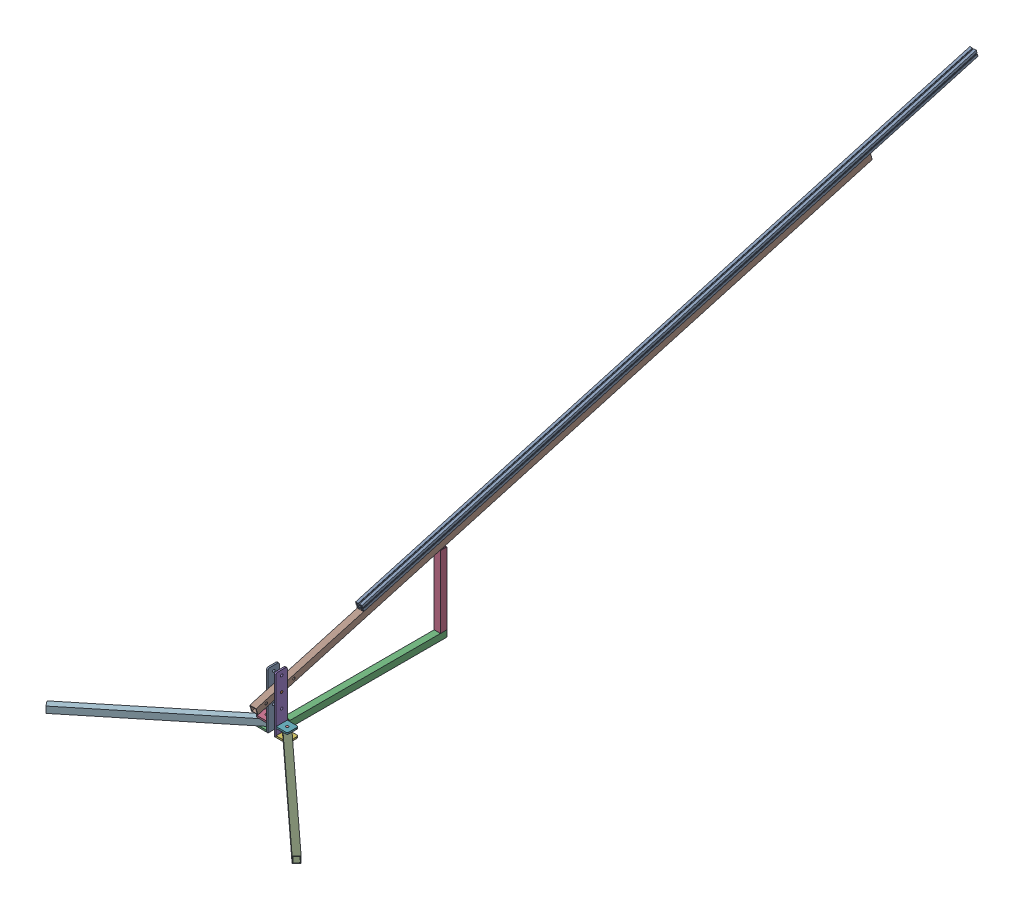
SolidWorks assembly plataformaDeLansamiento, configuration Predeterminado. Lengths in mm.
Overall size (1637.54 1526.39 5050.55).
16 component instances, 8 part files, 39 mates.
Components (placement in the parent):
- soporteEsctructura-1: soporteEsctructura [Predeterminado] at (70.7592 -29.7484 26.1138) x (0 0 -1) z (0 -1 0) size (70 10 350)
- union-1: union [Predeterminado] at (130.7592 25.2516 26.1138) x (0 -0.796552 0.604571) z (0 -0.604571 -0.796552) size (15 60 15)
- soporteLateral-1: soporteLateral [Predeterminado] at (35.7592 -194.7484 26.1138) x (0 0 -1) z (-1 0 0) size (70 10 70)
- soporteLateral-2: soporteLateral [Predeterminado] at (35.7592 -154.7484 26.1138) x (0 0 1) z (-1 0 0) size (70 10 70)
- soporteEsctructura-3: soporteEsctructura [Predeterminado] at (120.7592 -29.7484 26.1138) x (0 0 -1) z (0 -1 0) size (70 10 350)
- soporteLateral-3: soporteLateral [Predeterminado] at (165.7592 -204.7484 26.1138) x (0 0 -1) z (1 0 0) size (70 10 70)
- soporteLateral-4: soporteLateral [Predeterminado] at (165.7592 -154.7484 26.1138) x (0 0 -1) z (1 0 0) size (70 10 70)
- metalCuadrado-2: metalCuadrado [Predeterminado] at (100.7592 1073.3418 -3678.4789) x (1 0 0) z (0 -0.272231 0.962232) size (40 40 4000)
- soportePiso-1: soportePiso [Predeterminado] at (151.033 -174.7484 12.581) x (-0.676642 0 0.736312) z (0 1 0) size (40 1000 40)
- union-2: union [Predeterminado] at (165.7592 -204.7484 26.1138) size (15 60 15)
- union-3: union [Predeterminado] at (35.7592 -204.7484 26.1138) size (15 60 15)
- soportePiso-3: soportePiso [Predeterminado] at (51.2651 -174.7484 13.4818) x (0.631599 0 0.775295) z (0 -1 0) size (40 1000 40)
- aluminiumStructural-2: aluminiumStructural [Predeterminado] at (100.7592 1302.393 -4341.1519) x (1 0 0) z (0 -0.272231 0.962232) size (40 40 4000)
- soldarPieza-1: soldarPieza [Predeterminado] at (100.7592 -174.7484 -18.8862) size (60 60 10)
- soportePiso-4: soportePiso [Predeterminado] at (100.7592 -184.7484 -1018.8862) x (1 0 0) z (0 -1 0) size (40 1000 40)
- soporteSecundario-1: soporteSecundario [Predeterminado] at (100.7592 -164.7484 -998.8862) x (1 0 0) z (0 1 0) size (40 40 450)
Mates (geometry in assembly coordinates):
- Concéntrica2: concentric aligned: circle of soporteEsctructura-1; cylinder of union-1 through (70.7592 24.3437 26.1138) axis (1 0 0) radius 7.5
- Coincidente2: coincident aligned: plane of soporteEsctructura-1 through (70.7592 135.2516 51.1138) normal (-1 0 0); plane of union-1 through (70.7592 24.3437 26.1138) normal (-1 0 0)
- Coincidente3: coincident anti-aligned: plane of soporteEsctructura-1 through (70.7592 135.2516 51.1138) normal (-1 0 0); plane of soporteLateral-1 through (70.7592 -203.8405 61.1138) normal (1 0 0)
- Coincidente4: coincident aligned: plane of soporteEsctructura-1 through (80.7592 -204.7484 61.1138) normal (0 0 1); plane of soporteLateral-1 through (70.7592 -203.8405 61.1138) normal (0 0 1)
- Coincidente5: coincident aligned: plane of soporteEsctructura-1 through (80.7592 -204.7484 61.1138) normal (0 -1 0); plane of soporteLateral-1 through (10.7592 -203.8405 51.1138) normal (0 -1 0)
- Coincidente6: coincident anti-aligned: plane of soporteEsctructura-1 through (70.7592 135.2516 51.1138) normal (-1 0 0); plane of soporteLateral-2 through (70.7592 -143.8405 -8.8862) normal (1 0 0)
- Coincidente7: coincident aligned: plane of soporteEsctructura-1 through (80.7592 -204.7484 61.1138) normal (0 0 1); plane of soporteLateral-2 through (70.7592 -143.8405 61.1138) normal (0 0 1)
- Distancia1: distance = 40 mm: line of soporteLateral-1 through (70.7592 -194.7484 61.1138) axis (-1 0 0); line of soporteLateral-2 through (10.7592 -154.7484 61.1138) axis (1 0 0)
- Coincidente8: coincident aligned: plane of union-1 through (130.7592 24.3437 26.1138) normal (1 0 0); circle of soporteEsctructura-3
- Coincidente9: coincident anti-aligned: plane of soporteEsctructura-3 through (130.7592 135.2516 51.1138) normal (1 0 0); plane of soporteLateral-3 through (130.7592 -193.8405 61.1138) normal (-1 0 0)
- Coincidente10: coincident aligned: plane of soporteEsctructura-3 through (130.7592 -204.7484 61.1138) normal (0 0 1); plane of soporteLateral-3 through (130.7592 -193.8405 61.1138) normal (0 0 1)
- Coincidente11: coincident aligned: plane of soporteEsctructura-3 through (130.7592 -204.7484 61.1138) normal (0 -1 0); plane of soporteLateral-3 through (190.7592 -203.8405 51.1138) normal (0 -1 0)
- Coincidente12: coincident aligned: plane of soporteEsctructura-3 through (130.7592 -204.7484 61.1138) normal (0 0 1); plane of soporteLateral-4 through (130.7592 -143.8405 61.1138) normal (0 0 1)
- Coincidente13: coincident anti-aligned: plane of soporteEsctructura-3 through (130.7592 135.2516 51.1138) normal (1 0 0); plane of soporteLateral-4 through (130.7592 -143.8405 61.1138) normal (-1 0 0)
- Distancia2: distance = 40 mm: line of soporteLateral-3 through (130.7592 -194.7484 61.1138) axis (1 0 0); line of soporteLateral-4 through (130.7592 -154.7484 61.1138) axis (1 0 0)
- Coincidente14: coincident aligned: plane of soporteEsctructura-1 through (80.7592 145.2516 51.1138) normal (0 1 0); plane of soporteEsctructura-3 through (130.7592 145.2516 51.1138) normal (0 1 0)
- Coincidente15: coincident aligned: plane of soporteEsctructura-1 through (80.7592 -204.7484 -8.8862) normal (0 0 -1); plane of soporteEsctructura-3 through (130.7592 -204.7484 -8.8862) normal (0 0 -1)
- Concéntrica3: concentric aligned: cylinder of union-1 through (70.7592 24.3437 26.1138) axis (1 0 0) radius 7.5; circle of metalCuadrado-2
- Coincidente16: coincident anti-aligned: plane of soporteEsctructura-3 through (120.7592 135.2516 51.1138) normal (-1 0 0); plane of metalCuadrado-2 through (120.7592 -17.2445 171.6144) normal (1 0 0)
- Concéntrica4: concentric anti-aligned: circle of soporteLateral-4; cylinder of union-2 through (165.7592 -143.8405 26.1138) axis (0 -1 0) radius 7.5
- Coincidente17: coincident aligned: plane of soporteLateral-4 through (190.7592 -143.8405 51.1138) normal (0 1 0); plane of union-2 through (165.7592 -143.8405 26.1138) normal (0 1 0)
- Concéntrica5: concentric aligned: circle of soportePiso-1; cylinder of union-2 through (165.7592 -143.8405 26.1138) axis (0 -1 0) radius 7.5
- Coincidente18: coincident anti-aligned: plane of soporteLateral-4 through (190.7592 -153.8405 51.1138) normal (0 -1 0); plane of soportePiso-1 through (900.878 -153.8405 674.4967) normal (0 1 0)
- Concéntrica7: concentric anti-aligned: circle of soporteLateral-2; cylinder of union-3 through (35.7592 -143.8405 26.1138) axis (0 -1 0) radius 7.5
- Coincidente20: coincident aligned: plane of soporteLateral-2 through (10.7592 -143.8405 1.1138) normal (0 1 0); plane of union-3 through (35.7592 -143.8405 26.1138) normal (0 1 0)
- Concéntrica8: concentric aligned: cylinder of union-3 through (35.7592 -143.8405 26.1138) axis (0 -1 0) radius 7.5; circle of soportePiso-3
- Coincidente22: coincident anti-aligned: plane of soporteLateral-2 through (10.7592 -153.8405 1.1138) normal (0 -1 0); plane of soportePiso-3 through (-736.6619 -153.8405 629.5752) normal (0 1 0)
- Coincidente26: coincident anti-aligned: plane of metalCuadrado-2 through (80.7592 -17.2445 171.6144) normal (0 0.916739 0.399486); plane of aluminiumStructural-2 through (100.7592 262.3959 -470.103) normal (0 -0.916739 -0.399486)
- Coincidente27: coincident aligned: plane of metalCuadrado-2 through (80.7592 -17.2445 171.6144) normal (-1 0 0); plane of aluminiumStructural-2 through (80.7592 280.7307 -462.1133) normal (-1 0 0)
- Distancia3: distance = 700 mm: line of metalCuadrado-2 through (120.7592 1092.5865 -3673.0342) axis (-1 0 0); line of aluminiumStructural-2 through (80.7592 1283.1483 -4346.5965) axis (1 0 0)
- Coincidente28: coincident anti-aligned: plane of soporteEsctructura-1 through (80.7592 -204.7484 -8.8862) normal (0 0 -1); plane of soldarPieza-1 through (100.7592 -173.8405 -8.8862) normal (0 0 1)
- Coincidente29: coincident aligned: plane of soporteEsctructura-1 through (80.7592 -204.7484 61.1138) normal (0 -1 0); plane of soldarPieza-1 through (70.7592 -203.8405 -8.8862) normal (0 -1 0)
- Coincidente30: coincident aligned: plane of soporteEsctructura-1 through (70.7592 135.2516 51.1138) normal (-1 0 0); plane of soldarPieza-1 through (70.7592 -143.8405 -8.8862) normal (-1 0 0)
- Coincidente31: coincident anti-aligned: plane of soldarPieza-1 through (100.7592 -173.8405 -18.8862) normal (0 0 -1); plane of soportePiso-4 through (100.7592 -183.8405 -18.8862) normal (0 0 1)
- Coincidente32: coincident aligned: plane of soldarPieza-1 through (70.7592 -203.8405 -8.8862) normal (0 -1 0); plane of soportePiso-4 through (80.7592 -203.8405 -18.8862) normal (0 -1 0)
- Distancia4: distance = 10 mm: line of soportePiso-4 through (80.7592 -164.7484 -18.8862) axis (0 -1 0); line of soldarPieza-1 through (70.7592 -144.7484 -18.8862) axis (0 -1 0)
- Coincidente33: coincident anti-aligned: plane of soportePiso-4 through (80.7592 -163.8405 -18.8862) normal (0 1 0); plane of soporteSecundario-1 through (100.7592 -164.7484 -998.8862) normal (0 -1 0)
- Coincidente34: coincident aligned: plane of soportePiso-4 through (120.7592 -163.8405 -18.8862) normal (1 0 0); plane of soporteSecundario-1 through (120.7592 285.2516 -1018.8862) normal (1 0 0)
- Coincidente35: coincident aligned: plane of soportePiso-4 through (100.7592 -183.8405 -1018.8862) normal (0 0 -1); plane of soporteSecundario-1 through (80.7592 285.2516 -1018.8862) normal (0 0 -1)
